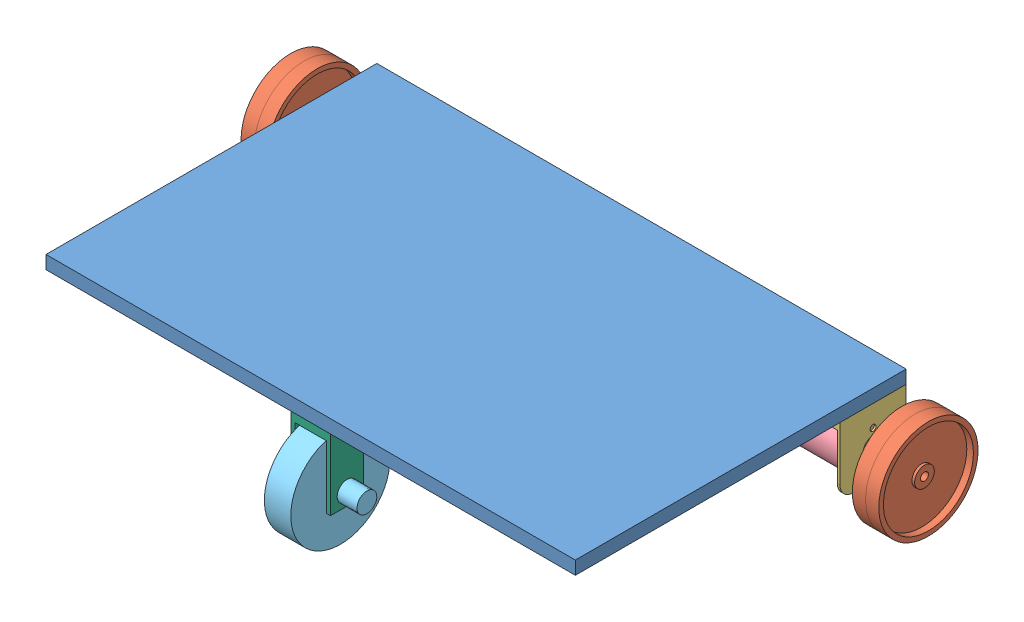
SolidWorks assembly final_assembly, configuration Default. Lengths in mm.
Overall size (481.9 119.84 317.34).
9 component instances, 6 part files, 15 mates.
Components (placement in the parent):
- base_part_1-1: base_part_1 [Default] at (-185.1254 3.4994 111.3765) size (400 10 250)
- Part3-1: Part3 [Default] at (-225.2095 -25.0006 -113.6235) x (0 -0.961239 -0.275716) z (0 -0.275716 0.961239) size (75 30 75)
- Part3-2: Part3 [Default] at (256.6868 -25.0006 -113.6235) x (0 0.547967 0.8365) z (0 -0.8365 0.547967) size (75 30 75)
- base_part_new-1: base_part_new [Default] at (-185.1254 -47.5006 -138.6235) x (0 0 -1) z (0 -1 0) size (50 25 51)
- base_part_new-2: base_part_new [Default] at (214.8746 -47.5006 -88.6235) x (0 0 1) z (0 -1 0) size (50 25 51)
- motor-1: motor [Default] at (168.5883 -25.0006 -113.6235) x (0 -0.288067 0.95761) z (0 0.95761 0.288067) size (38 78 38)
- motor-2: motor [Default] at (-139.2925 -25.0006 -113.6235) x (0 0.999798 -0.020091) z (0 0.020091 0.999798) size (38 78 38)
- steering_wwheel-1: steering_wwheel [Default] at (4.8746 -40.0006 98.8765) x (0 0.660484 -0.750841) z (0 -0.750841 -0.660484) size (75 60 75)
- clamp_for_steering_wheel-1: clamp_for_steering_wheel [Default] at (-0.1254 -2.5006 111.3765) size (30 53.5 25)
Mates (geometry in assembly coordinates):
- Coincident1: coincident anti-aligned: plane of base_part_1-1 through (-185.1254 3.4994 111.3765) normal (0 -1 0); plane of base_part_new-1 through (-185.1254 3.4994 -138.6235) normal (0 1 0)
- Coincident2: coincident aligned: plane of base_part_1-1 through (-185.1254 13.4994 111.3765) normal (-1 0 0); plane of base_part_new-1 through (-185.1254 -37.5006 -98.6235) normal (-1 0 0)
- Coincident3: coincident anti-aligned: plane of base_part_1-1 through (-185.1254 3.4994 111.3765) normal (0 -1 0); plane of base_part_new-2 through (214.8746 3.4994 -88.6235) normal (0 1 0)
- Coincident4: coincident aligned: plane of base_part_1-1 through (214.8746 13.4994 111.3765) normal (1 0 0); plane of base_part_new-2 through (214.8746 -37.5006 -128.6235) normal (1 0 0)
- Coincident5: coincident aligned: plane of base_part_1-1 through (-185.1254 13.4994 -138.6235) normal (0 0 -1); plane of base_part_new-2 through (212.8746 -37.5006 -138.6235) normal (0 0 -1)
- Coincident6: coincident aligned: plane of base_part_1-1 through (-185.1254 13.4994 -138.6235) normal (0 0 -1); plane of base_part_new-1 through (-183.1254 -37.5006 -138.6235) normal (0 0 -1)
- Concentric2: concentric anti-aligned: circle of base_part_new-2; circle of motor-1
- Coincident11: coincident aligned: circle of Part3-2; cylinder of motor-1 through (246.5883 -25.0006 -113.6235) axis (-1 0 0) radius 3
- Concentric3: concentric anti-aligned: circle of base_part_new-1; circle of motor-2
- Coincident12: coincident aligned: circle of Part3-1; cylinder of motor-2 through (-217.2925 -25.0006 -113.6235) axis (1 0 0) radius 3
- Width1: width anti-aligned: plane of steering_wwheel-1 through (4.8746 -40.0006 98.8765) normal (-1 0 0); plane of steering_wwheel-1 through (24.8746 -40.0006 98.8765) normal (1 0 0); plane of clamp_for_steering_wheel-1 through (2.8746 -50.0006 111.3765) normal (1 0 0); plane of clamp_for_steering_wheel-1 through (26.8746 -50.0006 111.3765) normal (-1 0 0)
- Coincident14: coincident anti-aligned: cylinder of steering_wwheel-1 through (-15.1254 -40.0006 98.8765) axis (1 0 0) radius 7.5; circle of clamp_for_steering_wheel-1
- Coincident15: coincident anti-aligned: plane of base_part_1-1 through (-185.1254 3.4994 111.3765) normal (0 -1 0); plane of clamp_for_steering_wheel-1 through (-0.1254 3.4994 111.3765) normal (0 1 0)
- Coincident16: coincident aligned: plane of base_part_1-1 through (-185.1254 13.4994 111.3765) normal (0 0 1); plane of clamp_for_steering_wheel-1 through (-0.1254 3.4994 111.3765) normal (0 0 1)
- Distance1: distance = 185 mm aligned: plane of clamp_for_steering_wheel-1 through (-0.1254 3.4994 111.3765) normal (-1 0 0); plane of base_part_1-1 through (-185.1254 13.4994 111.3765) normal (-1 0 0)
